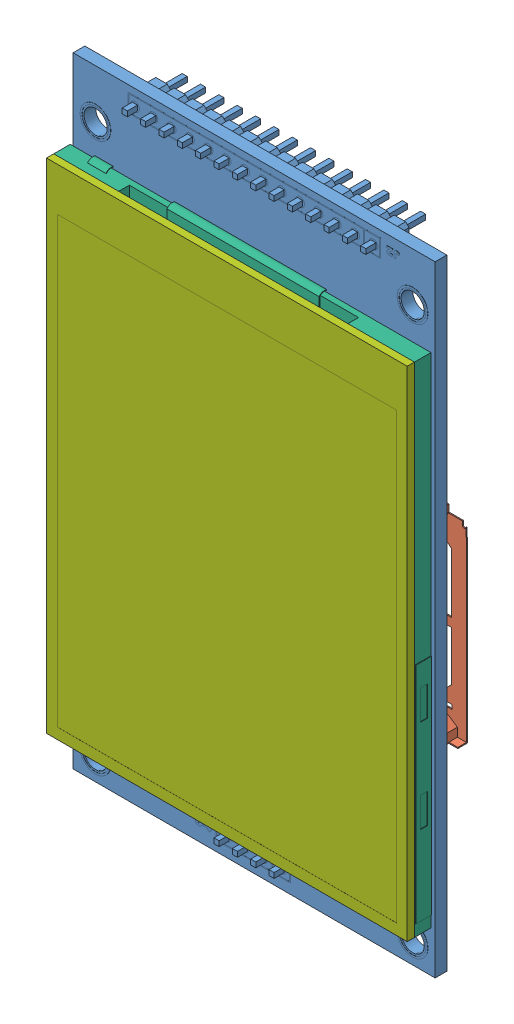
SolidWorks assembly 2.8 TFT Module_mod2, configuration Default. Lengths in mm.
Overall size (50.19 87.49 14.17).
15 component instances, 7 part files, 3 mates.
Components (placement in the parent):
- 2.8 TFT Module.stp-1: 2.8 TFT Module.stp [Default] at origin size (50.19 85.9 11.99)
  - 2.8 LCD TFT Module - Without Glass.stp-1: 2.8 LCD TFT Module - Without Glass.stp [Default] at origin size (50.14 85.9 10.67)
  - 5035000993.stp-1: 5035000993.stp [Default] at (3.5564 -3.3047 -2.85) x (0 1 0) z (0 0 -1) size (28.6 21.52 2.95)
  - 0603 Resistor.stp-1: 0603 Resistor.stp [Default] at (-2.2311 -3.165 0.0025) x (-1 0 0) z (0 0 -1) size (1.6 0.85 0.56)
  - 0603 Capacitor.stp-1: 0603 Capacitor.stp [Default] at (-14.5217 25.6289 0.0025) x (1 0 0) z (0 0 -1) size (1.6 0.84 0.84)
  - 0603 Capacitor.stp-2: 0603 Capacitor.stp [Default] at (-2.484 19.738 0.0025) x (-1 0 0) z (0 0 -1) size (1.6 0.84 0.84)
  - 0603 Resistor.stp-2: 0603 Resistor.stp [Default] at (-3.8795 -4.7617 0.0025) x (1 0 0) z (0 0 -1) size (1.6 0.85 0.56)
  - 0603 Resistor.stp-3: 0603 Resistor.stp [Default] at (-2.3355 -0.9936 0.0025) x (-1 0 0) z (0 0 -1) size (1.6 0.85 0.56)
  - 0603 Resistor.stp-4: 0603 Resistor.stp [Default] at (-12.9341 26.6747 0.0025) x (-1 0 0) z (0 0 -1) size (1.6 0.85 0.56)
  - 0603 Resistor.stp-5: 0603 Resistor.stp [Default] at (4.5338 19.5922 0.0025) x (-1 0 0) z (0 0 -1) size (1.6 0.85 0.56)
  - 0603 Resistor.stp-6: 0603 Resistor.stp [Default] at (4.3803 26.5372 0.0025) x (-1 0 0) z (0 0 -1) size (1.6 0.85 0.56)
  - SOT23-3.stp-1: SOT23-3.stp [Default] at (3.6167 23.9432 0.105) x (0.003406 0.999994 0) z (0 0 -1) size (2.9 3.01 1.23)
  - SOT23-3.stp-2: SOT23-3.stp [Default] at (-3.3735 23.944 0.105) x (0.999985 -0.005499 0) z (0 0 -1) size (2.9 3.01 1.23)
  - 2.8in TFT(Without Glass)- Tucked Cable.stp-1: 2.8in TFT(Without Glass)- Tucked Cable.stp [Default] at (-0.0571 -2.2987 1.6256) x (-1 0 0) z (0 0 1) size (50.11 69.48 2.83)
- GLASS-1: GLASS [Default] at (24.922 -36.8028 4.3434) x (-1 0 0) z (0 1 0) size (49.96 1 69.01)
Mates (geometry in assembly coordinates):
- Coincident3: coincident anti-aligned: plane of 2.8 TFT Module.stp-1/2.8in TFT(Without Glass)- Tucked Cable.stp-1 through (-0.0571 -2.2987 4.3434) normal (0 0 1); plane of GLASS-1 through (24.922 -36.8028 4.3434) normal (0 0 -1)
- Coincident4: coincident aligned: plane of 2.8 TFT Module.stp-1/2.8in TFT(Without Glass)- Tucked Cable.stp-1 through (-25.038 -36.8046 4.3434) normal (-1 0 0); plane of GLASS-1 through (-25.038 -36.8028 5.3434) normal (-1 0 0)
- Coincident5: coincident aligned: plane of 2.8 TFT Module.stp-1/2.8in TFT(Without Glass)- Tucked Cable.stp-1 through (-25.038 32.2072 4.3434) normal (0 1 0); plane of GLASS-1 through (24.922 32.2072 5.3434) normal (0 1 0)
